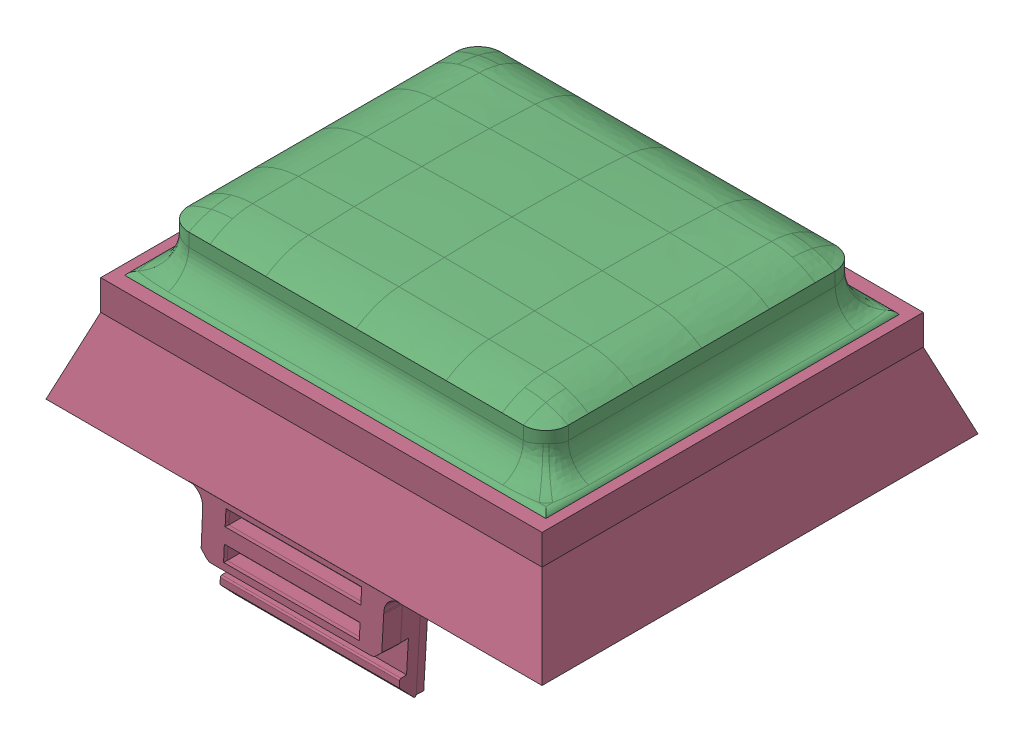
SolidWorks assembly CoordALL, configuration 默认. Lengths in mm.
Overall size (33 18.3 29.5).
5 component instances, 5 part files, 13 mates.
Components (placement in the parent):
- Coordlensall-1: Coordlensall [默认] at origin size (28.33 2.18 23.83)
- CoordInsideSkin-1: CoordInsideSkin [默认] at (0.0001 0 0.2499) size (23.8 5.48 19.29)
- CoordTopskin-1: CoordTopskin [默认] at (0.0001 2 0.2499) size (28.02 6.25 23.52)
- CoordSupportBase-2: CoordSupportBase [默认] at origin size (33 14.05 29.5)
- CoordinateMarker-1: CoordinateMarker [默认] at (-1.2748 23.7 0.6861) x (1 0 0) z (0 -1 0) size (23.6 17.6 1.5)
Mates (geometry in assembly coordinates):
- 同心2: concentric anti-aligned: cylinder of InsideSkin-1 through (10.8751 17.7531 8.6249) axis (0 1 0) radius 0.7; cylinder of Board3Con1612611OriginalSkin_TOP-1 through (10.8751 24 8.6249) axis (0 -1 0) radius 0.7
- 同心3: concentric anti-aligned: cylinder of InsideSkin-1 through (10.8751 17.7531 -9.1251) axis (0 1 0) radius 0.7; cylinder of Board3Con1612611OriginalSkin_TOP-1 through (10.8751 24 -9.1251) axis (0 -1 0) radius 0.7
- 重合4: coincident aligned: plane of InsideSkin-1 through (10.8751 19 -9.1251) normal (0 -1 0); plane of Board3Con1612611OriginalSkin_TOP-1 through (0.0001 19 0.2499) normal (0 -1 0)
- 重合6: coordinate: point of SupportBase-2
- 重合7: coincident anti-aligned: plane of lensall-1 through (13.75 19 -11.5) normal (0.939693 0.34202 0); plane of SupportBase-2 through (13.75 19 12.7803) normal (-0.939693 -0.34202 0)
- 同心5: concentric aligned: cylinder of lensall-1 through (13.3294 18.6938 -11.0794) axis (-0.323616 0.889126 0.323616) radius 0.5; cylinder of SupportBase-2 through (10.7866 25.6801 -8.5366) axis (-0.323616 0.889126 0.323616) radius 0.5
- 重合8: coincident anti-aligned: plane of lensall-1 through (0 18 0) normal (0 -1 0); plane of SupportBase-2 through (0 18 0) normal (0 1 0)
- 重合9: coincident anti-aligned: plane of lensall-1 through (0 19 0) normal (0 1 0); plane of Board3Con1612611OriginalSkin_TOP-1 through (0.0001 19 0.2499) normal (0 -1 0)
- 重合10: coincident anti-aligned: plane of Board3Con1612611OriginalSkin_TOP-1 through (0.0001 19 11.7499) normal (0 0 1); plane of SupportBase-2 through (-13.5999 21 11.7499) normal (0 0 -1)
- 重合11: coincident anti-aligned: plane of Board3Con1612611OriginalSkin_TOP-1 through (14.0001 19 0.2499) normal (1 0 0); plane of SupportBase-2 through (14.0001 21 11.7499) normal (-1 0 0)
- 宽度1: width: plane of CoordInsideSkin-1 through (-11.3749 17.7531 -9.8251) normal (0 0 -1); plane of CoordinateMarker-1 through (-11.3749 17.7531 9.3249) normal (0 0 1); plane of CoordInsideSkin-1 through (8.7501 25.4631 -9.0501) normal (0 0 -1); plane of CoordinateMarker-1 through (10.7501 25.4631 8.5499) normal (0 0 1)
- 宽度2: width: plane of CoordinateMarker-1 through (11.5501 25.4631 -0.2501) normal (1 0 0); plane of CoordInsideSkin-1 through (-12.0499 25.4631 1.7499) normal (-1 0 0); plane of CoordinateMarker-1 through (11.5751 17.7531 -9.1251) normal (1 0 0); plane of CoordInsideSkin-1 through (-12.0749 17.7531 -9.1251) normal (-1 0 0)
- 重合13: coincident aligned: circle of CoordInsideSkin-1; circle of CoordinateMarker-1
